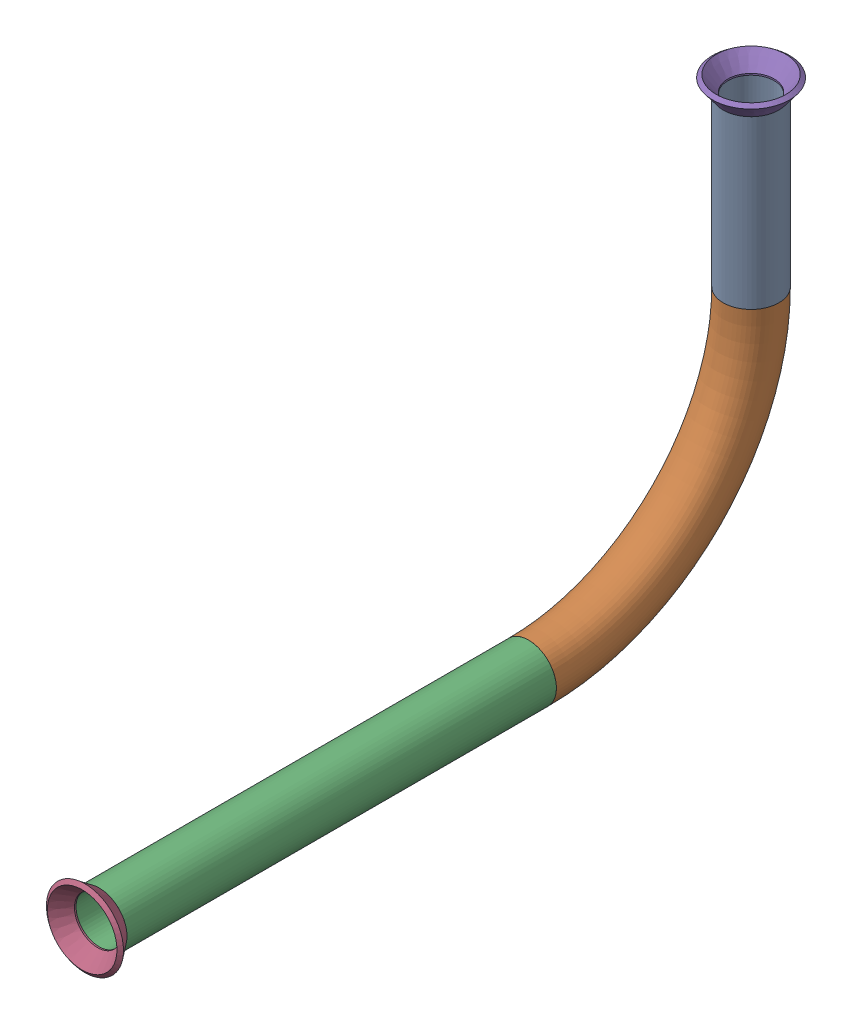
SolidWorks assembly Pipe 46, configuration Default. Lengths in mm.
Overall size (17.59 101.58 161.51).
3 component instances, 2 part files, 3 mates.
Components (placement in the parent):
- Part10-1: Part10 [Default<As Machined>] at origin size (12.7 95.25 155.18)
- Flared pipe end - .5 inch-1: Flared pipe end - .5 inch [Default<As Machined>] at (0 -331.5492 427.5775) x (0 1 0) z (0 0 1) size (17.59 17.59 3.89)
- Flared pipe end - .5 inch-2: Flared pipe end - .5 inch [Default<As Machined>] at (0 -242.6492 278.7482) x (0 0 -1) z (0 1 0) size (17.59 17.59 3.89)
Mates (geometry in assembly coordinates):
- Coincident1464: coincident: circle of Part10-1; circle of Flared pipe end - .5 inch-1
- Coincident1669: coincident: plane of Part10-1 through (0 -242.6492 278.7482) normal (0 1 0); plane of Flared pipe end - .5 inch-2 through (-5.2832 -242.6492 278.7482) normal (0 -1 0)
- Coincident1670: coincident: circle of Part10-1; circle of Flared pipe end - .5 inch-2
